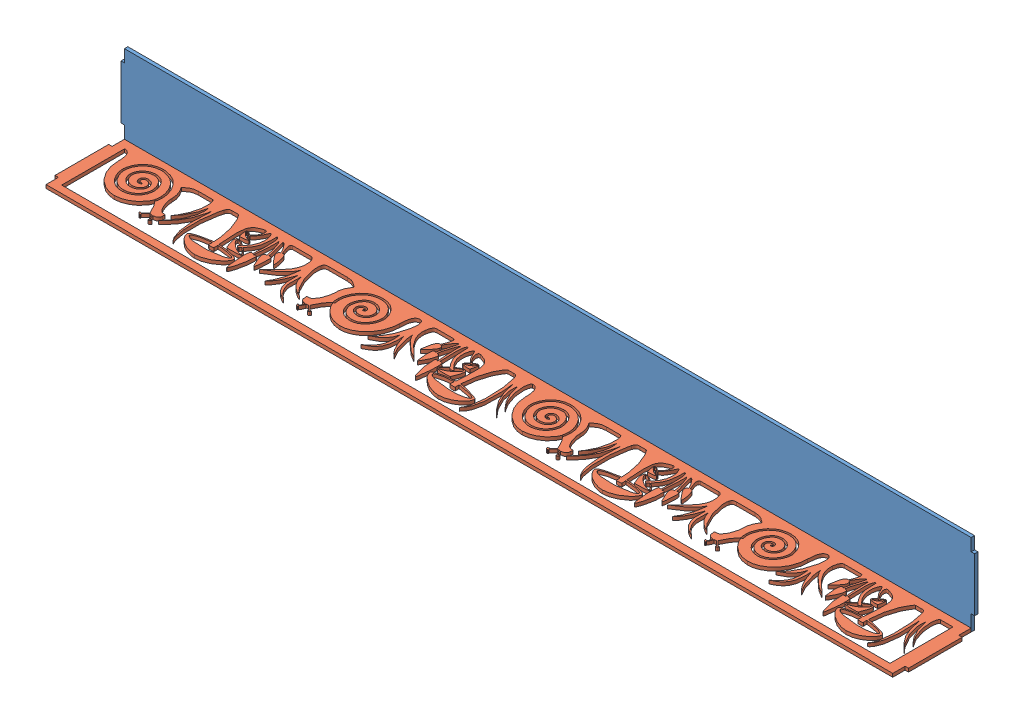
SolidWorks assembly Spicerack, configuration Default. Lengths in mm.
Overall size (794.35 76.23 76.17).
2 component instances, 2 part files, 3 mates.
Components (placement in the parent):
- Spicerack_bottom-1: Spicerack_bottom [Default] at (66.3776 576.7906 620.9352) size (794.35 76.17 3.17)
- Spicerack_front-1: Spicerack_front [Default] at (314.1576 526.369 508.4836) x (1 0 0) z (0 -1 0) size (794.35 76.18 3.28)
Mates (geometry in assembly coordinates):
- Coincident1: coincident anti-aligned: plane of Spicerack_bottom-1 through (66.3776 576.7906 624.1102) normal (0 0 1); plane of Spicerack_front-1 through (315.4279 523.194 624.1102) normal (0 0 -1)
- Coincident2: coincident anti-aligned: plane of Spicerack_bottom-1 through (6.4278 526.369 624.1102) normal (-1 0 0); plane of Spicerack_front-1 through (6.4278 523.194 624.1102) normal (1 0 0)
- Coincident3: coincident anti-aligned: plane of Spicerack_bottom-1 through (674.4278 526.369 624.1102) normal (0 -1 0); plane of Spicerack_front-1 through (314.1576 526.369 508.4836) normal (0 1 0)
